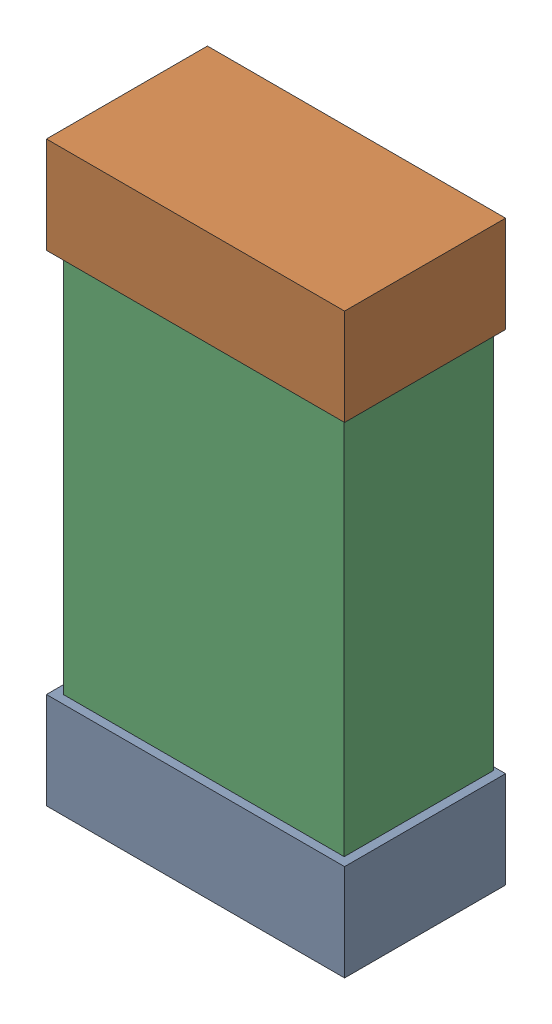
SolidWorks assembly C36, configuration Default. Lengths in mm.
Overall size (0.85 1.65 0.46).
6 component instances, 2 part files, 0 mates.
Components (placement in the parent):
- 432138512_50-1: 432138512_50 [Default] at (21.2403 61.4138 -0.8715) size (0.85 0.28 0.46)
  - Extruded-1: Extruded [Default] at origin size (0.85 0.28 0.46)
- 432138512_51-1: 432138512_51 [Default] at (21.2403 62.7853 -0.8715) size (0.85 0.28 0.46)
  - Extruded-1: Extruded [Default] at origin size (0.85 0.28 0.46)
- 432124816_25-1: 432124816_25 [Default] at (21.2403 62.0995 -0.8615) size (0.8 1.5 0.42)
  - Extruded (1)-1: Extruded (1) [Default] at origin size (0.8 1.5 0.42)
